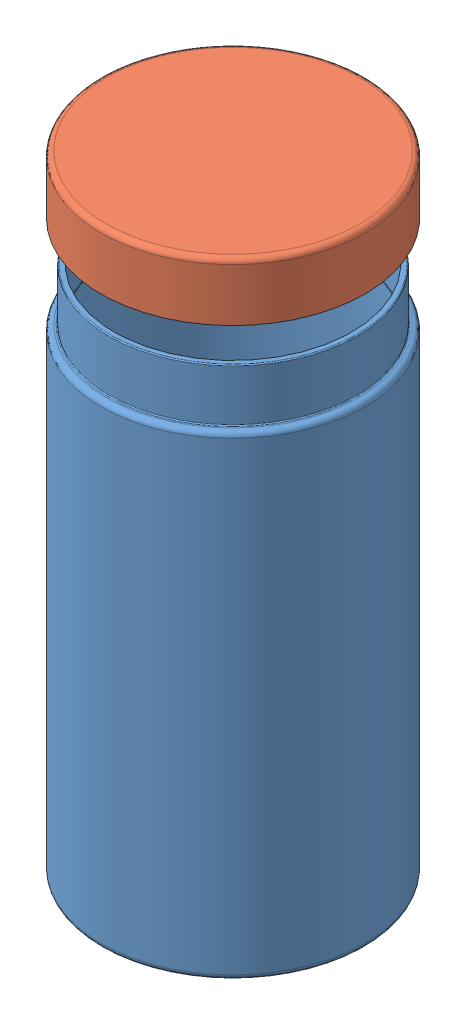
SolidWorks assembly Assem1, configuration Default. Lengths in mm.
Overall size (62.1 118.5 62.1).
2 component instances, 2 part files, 1 mates.
Components (placement in the parent):
- Part1-1: Part1 [Default] at (31.3185 -2.13 82.8611) size (50 100 50)
- Part2-1: Part2 [Default] at (31.3185 105.3691 82.8611) x (-0.959194 0 0.282749) z (-0.282749 0 -0.959194) size (50 11 50)
Mates (geometry in assembly coordinates):
- Concentric1: concentric aligned: circle of Part1-1; circle of Part2-1
